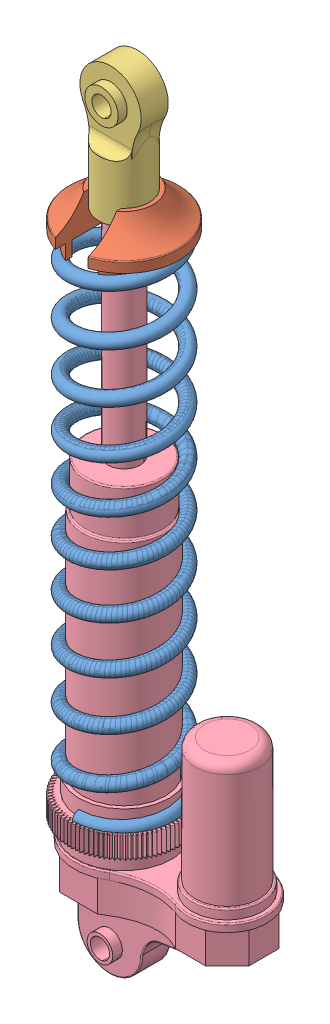
SolidWorks assembly KJ110FT33装配体, configuration 默认. Lengths in mm.
Overall size (36.96 121.95 16.99).
4 component instances, 4 part files, 0 mates.
Components (placement in the parent):
- KJ110FT33弹簧-1: KJ110FT33弹簧 [默认] at (-21.6288 -33.8 -0.0984) size (16.64 77.95 16.64)
- KJ110FT33端盖-1: KJ110FT33端盖 [默认] at (-21.6288 39.4 -0.0984) size (29.58 7.8 16.69)
- KJ110FT33端头-1: KJ110FT33端头 [默认] at (-21.6288 39.9 -0.0984) size (9.5 19.95 9.67)
- KJ110FT33框架-1: KJ110FT33框架 [默认] at (-21.6288 -45.3 -0.0984) size (30.67 102 16.99)
